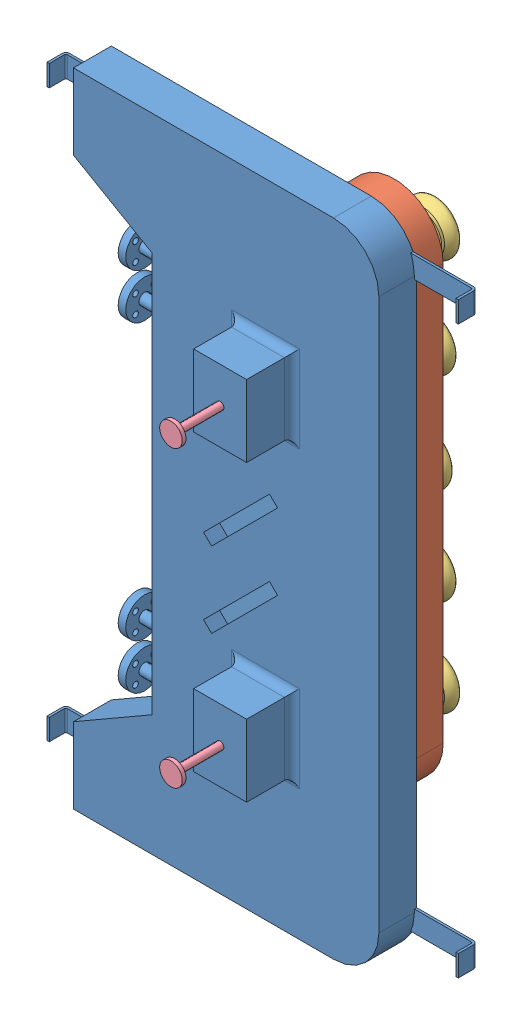
SolidWorks assembly Cap Assembly, configuration Default. Lengths in mm.
Overall size (690.28 1077.29 454.96).
30 component instances, 9 part files, 24 mates.
Components (placement in the parent):
- Top Cap-1: Top Cap [Default] at (0 0 3081.8977) size (690.28 1077.29 147.32)
- Plugs Fixer-2: Plugs Fixer [Default] at (327.3273 0 1939.3509) x (0 0 1) z (-1 0 0) size (76.2 861.39 164.5)
- Plug-1: Plug [Default] at (327.3273 0 2929.4977) x (-1 0 0) z (0 0 -1) size (98.84 98.84 202.97)
- Plug-2: Plug [Default] at (327.3273 164.5467 2935.8477) x (-1 0 0) z (0 0 -1) size (98.84 98.84 202.97)
- Plug-3: Plug [Default] at (-861.6126 1543.829 2942.1977) x (-0.219587 0.975593 0) z (0 0 -1) size (98.84 98.84 202.97)
- Plug-4: Plug [Default] at (327.3273 493.6401 2935.8477) x (-1 0 0) z (0 0 -1) size (98.84 98.84 202.97)
- Plug-5: Plug [Default] at (1603.584 1224.0286 2929.4977) x (-0.473539 -0.880773 0) z (0 0 -1) size (98.84 98.84 202.97)
- Damper Assembly-1: Damper Assembly [Default] at (0 0 3107.2977) x (-1 0 0) z (0 0 -1) size (38 38 377.82) (flexible)
  - Damper Rod-1: Damper Rod [Default] at (-301.9273 0 25.4) x (0 0 -1) z (1 0 0) size (377.82 38 38)
  - Damper Cylinder-1: Damper Cylinder [Default] at origin size (32.82 32.82 101.6)
  - O-Ring-1: O-Ring [Default] at (-492.1271 0 0) x (0 0 -1) z (1 0 0) size (1.27 26.37 26.37)
- Spacer-1: Spacer [Default] at (327.3273 0 3005.6977) size (70.92 70.92 13.97)
- Washer-1: Washer [Default] at (327.3273 0 3019.6677) size (68.38 68.38 1.59)
- Heavy Hex Flat Nut-1: Heavy Hex Flat Nut [Default] at (327.3273 0 3021.2552) size (70.92 61.42 23.81)
- Spacer-2: Spacer [Default] at (327.3273 164.5412 3005.6977) size (70.92 70.92 13.97)
- Spacer-3: Spacer [Default] at (327.3273 329.0824 3005.6977) size (70.92 70.92 13.97)
- Spacer-4: Spacer [Default] at (327.3273 493.6236 3005.6977) size (70.92 70.92 13.97)
- Spacer-5: Spacer [Default] at (327.3273 658.1648 3005.6977) size (70.92 70.92 13.97)
- Washer-3: Washer [Default] at (327.3273 164.5412 3019.6677) size (68.38 68.38 1.59)
- Washer-4: Washer [Default] at (327.3273 329.0824 3019.6677) size (68.38 68.38 1.59)
- Washer-5: Washer [Default] at (327.3273 493.6236 3019.6677) size (68.38 68.38 1.59)
- Washer-6: Washer [Default] at (327.3273 658.1648 3019.6677) size (68.38 68.38 1.59)
- Heavy Hex Flat Nut-2: Heavy Hex Flat Nut [Default] at (327.3273 164.5412 3021.2552) size (70.92 61.42 23.81)
- Heavy Hex Flat Nut-3: Heavy Hex Flat Nut [Default] at (327.3273 329.0824 3021.2552) size (70.92 61.42 23.81)
- Heavy Hex Flat Nut-4: Heavy Hex Flat Nut [Default] at (327.3273 493.6236 3021.2552) size (70.92 61.42 23.81)
- Heavy Hex Flat Nut-5: Heavy Hex Flat Nut [Default] at (327.3273 658.1648 3021.2552) size (70.92 61.42 23.81)
- Damper Assembly-2: Damper Assembly [Default] at (984.2542 3359.2148 3107.2977) x (1 0 0) z (0 0 -1) size (38 38 377.82)
  - Damper Rod-1: Damper Rod [Default] at (-301.9273 0 25.4) x (0 0 -1) z (1 0 0) size (377.82 38 38)
  - Damper Cylinder-1: Damper Cylinder [Default] at origin size (32.82 32.82 101.6)
  - O-Ring-1: O-Ring [Default] at (-492.1271 0 0) x (0 0 -1) z (1 0 0) size (1.27 26.37 26.37)
Mates (geometry in assembly coordinates):
- InPlace6: in place: plane of Plugs Fixer-2 through (492.1271 2028.051 2929.4977) normal (0 0 -1); plane of ? through (0 0 2929.4977) normal (0 0 -1); moOrthogonalPlaneRef_w of Plugs Fixer-2 through (492.1271 2028.051 2929.4977) normal (0 0 -1); unknown of ?; plane of Plugs Fixer-2 through (492.1271 2028.051 2929.4977) normal (0 0 -1); plane of ? through (0 0 2929.4977) normal (-1 0 0); plane of Plugs Fixer-2 through (492.1271 2028.051 2929.4977) normal (0 0 -1); unknown of Plug-1
- Coincident89: coincident aligned: plane of Plugs Fixer-2; plane of Plug-1
- Coincident90: coincident aligned: moOrthogonalPlaneRef_w of Plugs Fixer-2 through (327.3273 0 2929.4977) normal (0 1 0); plane of Plug-1 through (327.3273 0 2929.4977) normal (0 1 0)
- Coincident91: coincident anti-aligned: moOrthogonalPlaneRef_w of Plugs Fixer-2 through (327.3273 0 2929.4977) normal (1 0 0); plane of Plug-1 through (327.3273 0 2929.4977) normal (-1 0 0)
- Concentric10: concentric aligned: cylinder of Plugs Fixer-2 through (492.1271 1515.0607 2929.4967) axis (0 0 1) radius 22.86; cylinder of Plug-2 through (492.1271 1515.0607 2774.9573) axis (0 0 1) radius 22.7584
- Distance30: distance = 6.35 mm aligned: plane of Plug-2 through (492.1271 2192.5977 3057.7677) normal (0 0 1); plane of Plug-1 through (492.1271 2028.051 3051.4177) normal (0 0 1)
- Concentric11: concentric aligned: cylinder of Plugs Fixer-2 through (492.1271 1679.6074 2929.4967) axis (0 0 1) radius 22.86; cylinder of Plug-3 through (492.1271 1679.6074 2781.3073) axis (0 0 1) radius 22.7584
- Distance31: distance = 6.35 mm aligned: plane of Plug-3 through (1153.1274 1828.386 3064.1177) normal (0 0 1); plane of Plug-2 through (492.1271 2192.5977 3057.7677) normal (0 0 1)
- Concentric12: concentric aligned: cylinder of Plugs Fixer-2 through (492.1271 1844.1541 2929.4967) axis (0 0 1) radius 22.86; cylinder of Plug-4 through (492.1271 1844.1541 2774.9573) axis (0 0 1) radius 22.7584
- Coincident94: coincident aligned: plane of Plug-2 through (492.1271 2192.5977 3057.7677) normal (0 0 1); plane of Plug-4 through (492.1271 2521.6911 3057.7677) normal (0 0 1)
- Concentric131: concentric aligned: cylinder of Plugs Fixer-2 through (492.1271 2008.7008 2929.4967) axis (0 0 1) radius 22.86; cylinder of Plug-5 through (492.1271 2008.7008 2768.6073) axis (0 0 1) radius 22.7584
- Coincident951: coincident aligned: plane of Plug-1 through (492.1271 2028.051 3051.4177) normal (0 0 1); plane of Plug-5 through (-104.6291 2329.541 3051.4177) normal (0 0 1)
- InPlace9: in place: plane of Plugs Fixer-2 through (492.1271 2028.051 3005.6977) normal (0 0 1); plane of ? through (0 0 3005.6977) normal (0 0 1); plane of Plugs Fixer-2 through (492.1271 2028.051 3005.6977) normal (0 0 1); plane of ? through (0 0 3005.6977) normal (0 1 0); plane of Plugs Fixer-2 through (492.1271 2028.051 3005.6977) normal (0 0 1); plane of ? through (0 0 3005.6977) normal (1 0 0); plane of Plugs Fixer-2 through (492.1271 2028.051 3005.6977) normal (0 0 1); unknown of Spacer-1
- Coincident102: coincident aligned: plane of Plugs Fixer-2; plane of Spacer-1
- Coincident103: coincident aligned: moOrthogonalPlaneRef_w of Plugs Fixer-2 through (327.3273 0 3005.6977) normal (0 1 0); plane of Spacer-1 through (327.3273 0 3005.6977) normal (0 1 0)
- Coincident104: coincident anti-aligned: moOrthogonalPlaneRef_w of Plugs Fixer-2 through (327.3273 0 3005.6977) normal (-1 0 0); plane of Spacer-1 through (327.3273 0 3005.6977) normal (1 0 0)
- InPlace10: in place: plane of Spacer-1 through (492.1271 1350.514 3024.7477) normal (0 0 1); plane of ? through (0 0 3024.7477) normal (0 0 1); plane of Spacer-1 through (492.1271 1350.514 3024.7477) normal (0 0 1); plane of ? through (0 0 3024.7477) normal (0 1 0); plane of Spacer-1 through (492.1271 1350.514 3024.7477) normal (0 0 1); plane of ? through (0 0 3024.7477) normal (1 0 0); plane of Spacer-1 through (492.1271 1350.514 3019.6677) normal (0 0 1); unknown of Washer-1
- Coincident105: coincident aligned: plane of Spacer-1; plane of Washer-1
- Coincident106: coincident aligned: moOrthogonalPlaneRef_w of Spacer-1 through (327.3273 0 3019.6677) normal (0 1 0); plane of Washer-1 through (327.3273 0 3019.6677) normal (0 1 0)
- Coincident107: coincident anti-aligned: moOrthogonalPlaneRef_w of Spacer-1 through (327.3273 0 3019.6677) normal (-1 0 0); plane of Washer-1 through (327.3273 0 3019.6677) normal (1 0 0)
- InPlace11: in place: plane of Washer-1 through (492.1271 1350.514 3021.2552) normal (0 0 1); plane of ? through (0 0 3021.2552) normal (0 0 1); plane of Washer-1 through (492.1271 1350.514 3021.2552) normal (0 0 1); plane of ? through (0 0 3021.2552) normal (0 1 0); plane of Washer-1 through (492.1271 1350.514 3021.2552) normal (0 0 1); plane of ? through (0 0 3021.2552) normal (1 0 0); plane of Washer-1 through (492.1271 1350.514 3021.2552) normal (0 0 1); unknown of Heavy Hex Flat Nut-1
- Coincident108: coincident aligned: plane of Washer-1; plane of Heavy Hex Flat Nut-1
- Coincident109: coincident aligned: moOrthogonalPlaneRef_w of Washer-1 through (327.3273 0 3021.2552) normal (0 1 0); plane of Heavy Hex Flat Nut-1 through (327.3273 0 3021.2552) normal (0 1 0)
- Coincident110: coincident anti-aligned: moOrthogonalPlaneRef_w of Washer-1 through (327.3273 0 3021.2552) normal (-1 0 0); plane of Heavy Hex Flat Nut-1 through (327.3273 0 3021.2552) normal (1 0 0)
